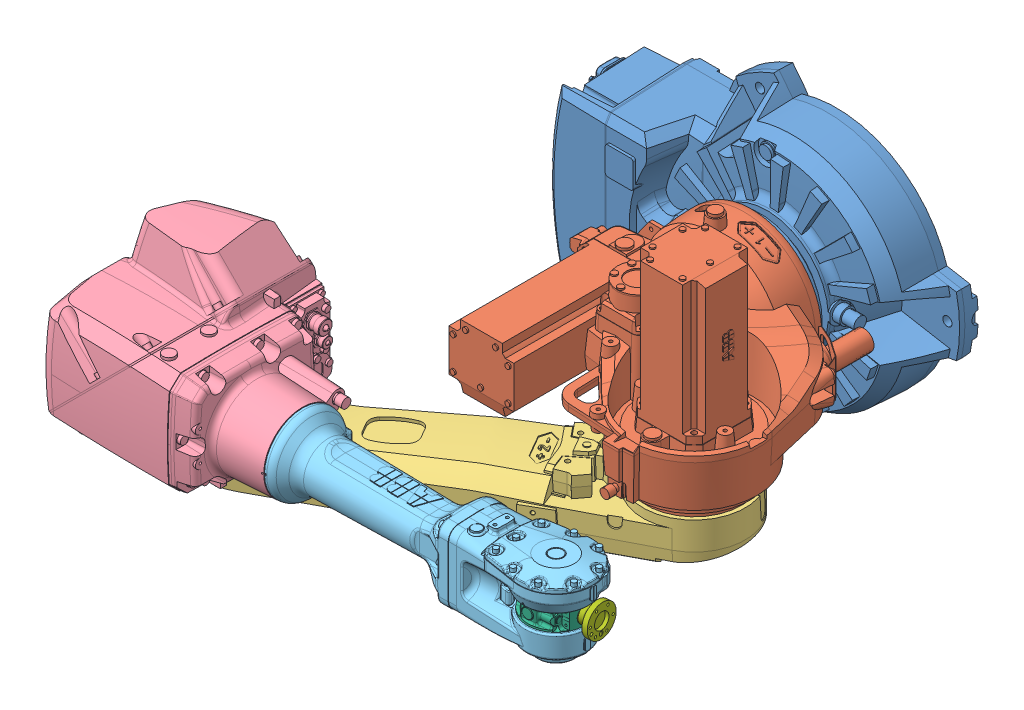
SolidWorks assembly IRB2600, configuration Default. Lengths in mm.
7 component instances, 7 part files, 15 mates.
Components (placement in the parent):
- IRB2600-Base-1: IRB2600-Base [Default] at origin size (698.24 514.54 232.1)
- IRB2600-Link 1-1: IRB2600-Link 1 [Default] at (0 0 -0.2) size (544 422.5 454)
- IRB2600-Link 2-1: IRB2600-Link 2 [Default] at (460.3813 0 92.3962) x (0.5 0 0.866025) z (-0.866025 0 0.5) size (214.89 150 881.79)
- IRB2600-Link 3-2: IRB2600-Link 3 [Default] at (-606.2178 0 -350.2) size (450.72 352.7 359.48)
- IRB2600-Link 4-4: IRB2600-Link 4 [Default] at (-606.2178 0 -350.2) size (583.5 167.71 153.36)
- IRB2600-Link 5-1: IRB2600-Link 5 [Default] at (-700.183 0 -273.9129) x (0.997047 0 -0.07679) z (0.07679 0 0.997047) size (114.6 41 114.89)
- IRB2600-Link 6-1: IRB2600-Link 6 [Default] at (-690.0427 561.5465 -142.2503) x (0.997047 0 -0.07679) z (0.068742 -0.445672 0.892553) size (34 63 63)
Mates (geometry in assembly coordinates):
- Coincident1: coincident: plane of assembly; plane of assembly; plane of IRB2600-Base-1 through (0 0 231.9) normal (0 0 1); plane of IRB2600-Link 1-1 through (0 0 231.9) normal (0 0 -1)
- Concentric1: concentric: cylinder of assembly; cylinder of assembly; cylinder of IRB2600-Base-1 through (0 0 232.1) axis (0 0 -1) radius 125; cylinder of IRB2600-Link 1-1 through (0 0 613.7377) axis (0 0 -1) radius 135
- Coincident2: coincident: plane of assembly; plane of assembly; plane of IRB2600-Link 1-1 through (150 -130 444.8) normal (0 -1 0); plane of IRB2600-Link 2-1 through (150 -130 444.8) normal (0 1 0)
- Concentric2: concentric: cylinder of assembly; cylinder of assembly; cylinder of IRB2600-Link 1-1 through (150 -126.1 444.8) axis (0 1 0) radius 93; cylinder of IRB2600-Link 2-1 through (150 -86.4 444.8) axis (0 -1 0) radius 94.5
- Coincident3: coincident: plane of IRB2600-Link 2-1 through (-520.8233 -150 832.1) normal (0 1 0); plane of ? through (-515.9258 -150 854.508) normal (0 -1 0)
- Concentric3: concentric: circle of IRB2600-Link 2-1; cylinder of ? through (-456.2178 -145 794.8) axis (0 -1 0) radius 16
- Coincident4: coincident: plane of ? through (-168.7178 -70.84 980.64) normal (1 0 0); plane of ? through (-168.7178 0 909.8) normal (-1 0 0)
- Concentric4: concentric: cone of ? through (-169.2178 0 909.8) axis (1 0 0); cylinder of ? through (-168.2178 0 909.8) axis (1 0 0) radius 52.3599
- Coincident6: coincident: plane of ? through (338.7822 -20.5 909.8) normal (0 1 0); plane of IRB2600-Link 5-1 through (343.1823 -20.5 966.9308) normal (0 -1 0)
- Concentric5: concentric: cylinder of ? through (338.7822 -21.7093 909.8) axis (0 -1 0) radius 69.8132; cylinder of IRB2600-Link 5-1 through (338.7822 74.2516 909.8) axis (0 1 0) radius 57.3
- Coincident7: coincident: plane of assembly; plane of assembly; plane of IRB2600-Link 5-1 through (389.6316 0 905.8837) normal (0.997047 0 -0.07679); plane of IRB2600-Link 6-1 through (390.4946 -33.5217 917.0886) normal (-0.997047 0 0.07679)
- Concentric6: concentric: cylinder of assembly; cylinder of assembly; cylinder of IRB2600-Link 5-1 through (411.8764 0 904.1705) axis (0.997047 0 -0.07679) radius 17.75; cylinder of IRB2600-Link 6-1 through (362.8007 0 907.9502) axis (-0.997047 0 0.07679) radius 17.5
- LimitAngle2: limit planar angle = 2.094395 rad: plane of assembly; plane of assembly; plane of IRB2600-Link 2-1 through (56.6058 -205.4 613.0365) normal (0.5 0 0.866025); plane of IRB2600-Link 1-1 through (215 11.5 379.8) normal (1 0 0)
- LimitAngle3: limit planar angle = 2.094395 rad: plane of ? through (-271.2178 14.8394 1022.3464) normal (1 0 0); plane of IRB2600-Link 2-1 through (56.6058 -205.4 613.0365) normal (0.5 0 0.866025)
- LimitAngle4: limit planar angle = 0 rad: plane of ? through (338.7822 -87.5 909.8) normal (0 -1 0); plane of ? through (-368.3618 -98 1001.944) normal (0 -1 0)
